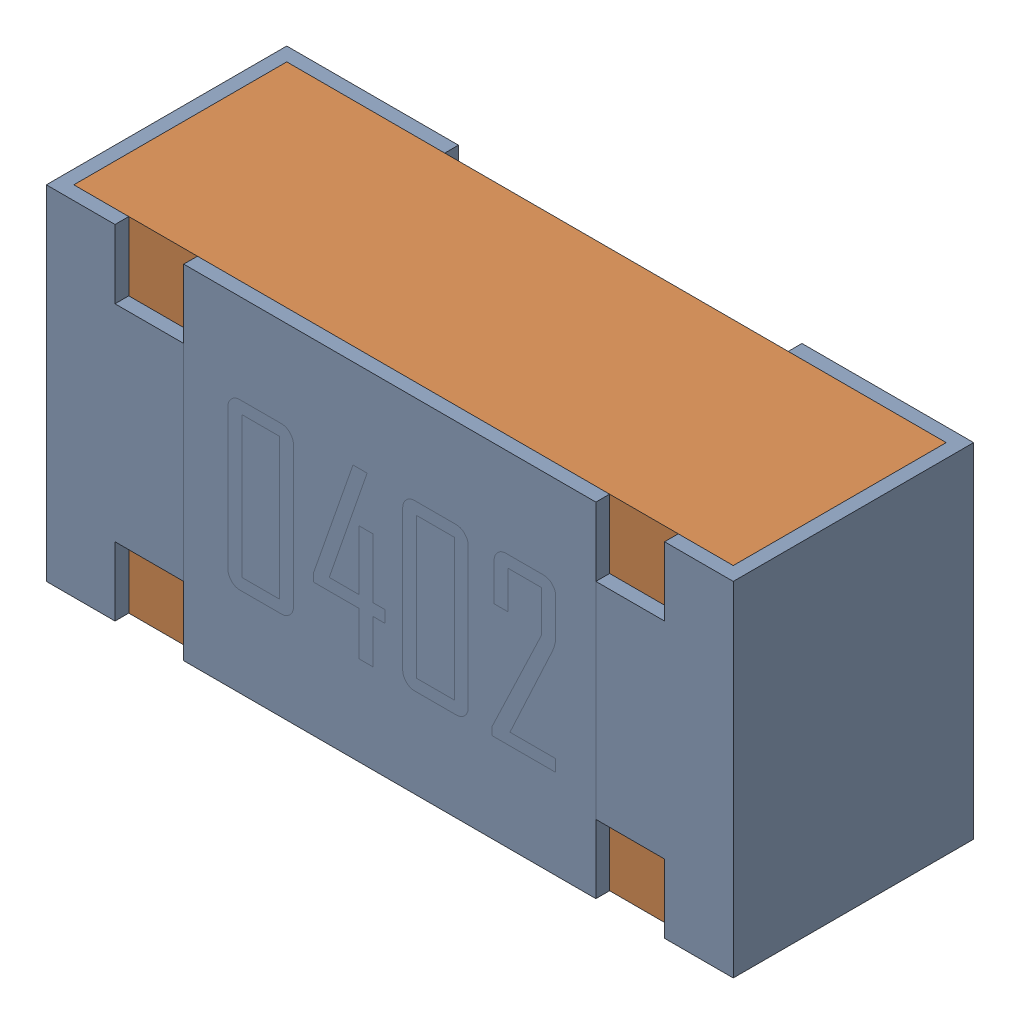
SolidWorks assembly R4, configuration Default. Lengths in mm.
Overall size (1 0.5 0.35).
3 component instances, 2 part files, 0 mates.
Components (placement in the parent):
- R4-subassembly-1-1: R4-subassembly-1 [Default] at (-15.5001 4 0) x (1 0 0) z (0 -1 0) size (1 0.35 0.5)
  - 0402 resistor-1: 0402 resistor [Default] at origin size (1 0.35 0.5)
  - 0402 resistor-1-1: 0402 resistor-1 [Default] at origin size (0.96 0.31 0.5)
